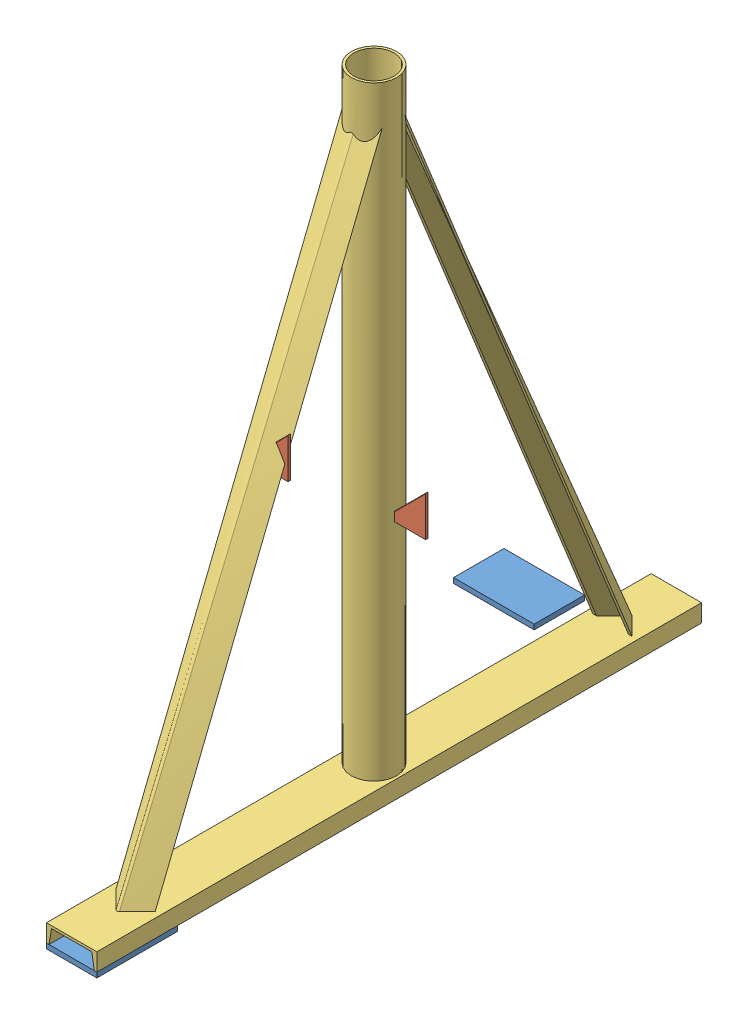
SolidWorks assembly Assem1, configuration Default. Lengths in mm.
Overall size (463.31 1581.15 1524).
5 component instances, 3 part files, 4 mates.
Components (placement in the parent):
- Part 2-1: Part 2 [Default] at (-30.7446 140.2661 83.6839) size (203.2 12.7 127)
- Part 6-1: Part 6 [Default] at (-92.3663 196.352 213.062) size (101.6 101.6 6.35)
- SA 1 Part-1: SA 1 Part [Default] at (-227.3564 -360.2468 -547.4491) size (127 1568.45 1524)
- Part 2-2: Part 2 [Default] at (-290.8564 -404.6968 976.5509) x (0 0 -1) z (1 0 0) size (203.2 12.7 127)
- Part 6-2: Part 6 [Default] at (-169.908 418.9183 482.3755) size (101.6 101.6 6.35)
Mates (geometry in assembly coordinates):
- Coincident1: coincident anti-aligned: plane of SA 1 Part-1 through (-170.2064 -404.6968 889.5569) normal (0 -1 0); plane of Part 2-2 through (-163.8564 -404.6968 976.5509) normal (0 1 0)
- Parallel1: parallel aligned: plane of SA 1 Part-1 through (-163.8564 -404.6968 889.5569) normal (1 0 0); plane of Part 2-2 through (-163.8564 -404.6968 976.5509) normal (1 0 0)
- Coincident3: coincident aligned: plane of SA 1 Part-1 through (-290.8564 -360.2468 976.5509) normal (-1 0 0); plane of Part 2-2 through (-290.8564 -404.6968 976.5509) normal (-1 0 0)
- Coincident4: coincident aligned: plane of SA 1 Part-1 through (-227.3564 -360.2468 976.5509) normal (0 0 1); plane of Part 2-2 through (-163.8564 -417.3968 976.5509) normal (0 0 1)
